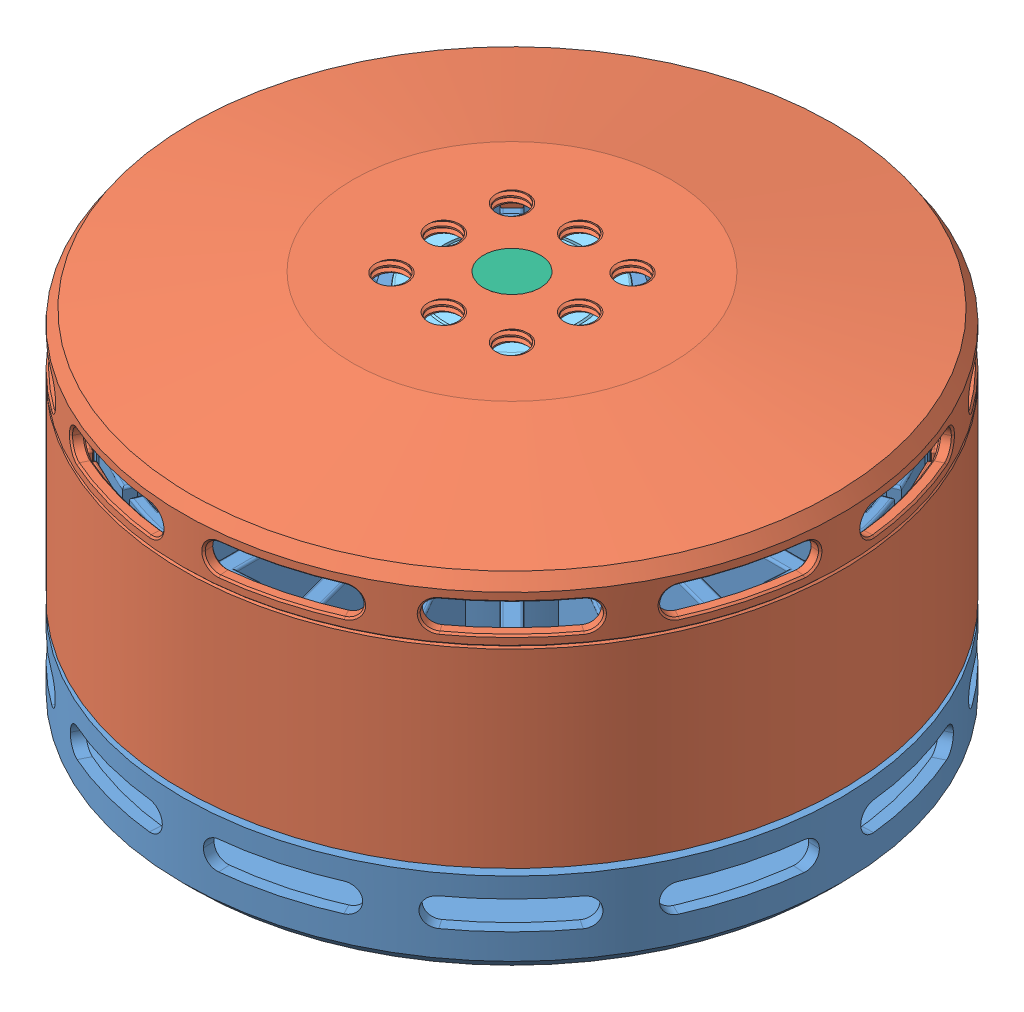
SolidWorks assembly MAD 5015 IPE V3 Motor Assembly, configuration Default. Lengths in mm.
Overall size (58 35.42 58).
29 component instances, 6 part files, 8 mates.
Components (placement in the parent):
- MAD 5015 IPE V3 Motor - Base-1: MAD 5015 IPE V3 Motor - Base [5015 IPE V3.0 ] at (22.8135 16.8969 43.0292) size (58 33.68 58)
- MAD 5015 IPE V3 Motor - Top-1: MAD 5015 IPE V3 Motor - Top [Default] at (22.8135 24.9802 43.0292) size (58 25.16 58)
- 696ZZ Bearing-1: 696ZZ Bearing [Default] at (22.7055 46.1225 47.1838) size (15.58 5 15.58)
  - ball bearing-3: ball bearing [Default] at (-8.9619 -2.7293 0.1818) x (0.444401 0.889708 -0.104533) z (0.713997 -0.281306 0.641152) size (2.7 2.7 2.7)
  - ball bearing-2: ball bearing [Default] at (-2.8221 2.4974 -4.5597) x (0.068858 0.146635 0.986791) z (-0.685148 -0.712022 0.153614) size (2.7 2.7 2.7)
  - ball bearing-1: ball bearing [Default] at (-3.7028 5.9901 -3.9309) x (0.28408 -0.958228 -0.033144) z (-0.506929 -0.179448 0.843102) size (2.7 2.7 2.7)
  - ball bearing-10: ball bearing [Default] at (-0.4124 2.7884 -8.0398) x (0.998941 0.024755 -0.038778) z (0.039629 -0.034863 0.998606) size (2.7 2.7 2.7)
  - ball bearing-8: ball bearing [Default] at (-3.307 1.4171 -7.6483) x (0.897908 0.343444 -0.27533) z (0.405535 -0.402192 0.820843) size (2.7 2.7 2.7)
  - ball bearing-7: ball bearing [Default] at (-7.5678 4.9126 -7.8607) x (0.925697 -0.372266 -0.067103) z (-0.05952 -0.318536 0.94604) size (2.7 2.7 2.7)
  - ball bearing-6: ball bearing [Default] at (0.3979 3.4094 -4.0154) x (0.993103 -0.041629 -0.109611) z (0.094371 -0.270991 0.957945) size (2.7 2.7 2.7)
  - ball bearing-9: ball bearing [Default] at (-6.0376 3.6584 -8.4022) x (0.983933 -0.065456 -0.166108) z (0.104106 -0.545494 0.831624) size (2.7 2.7 2.7)
  - ball bearing-4: ball bearing [Default] at (-2.7537 -0.7778 -2.9999) x (0.769778 0.563696 0.29948) z (-0.478994 0.20001 0.854728) size (2.7 2.7 2.7)
  - ball bearing-5: ball bearing [Default] at (-1.2092 -1.699 -1.9935) x (0.661202 0.749392 -0.034976) z (0.073954 -0.018714 0.997086) size (2.7 2.7 2.7)
  - 696ZZ Inner Bearing Race-1: 696ZZ Inner Bearing Race [Default] at (0.108 2.8577 -4.1547) size (9.15 5 9.15)
  - 696ZZ Outer Bearing Race-1: 696ZZ Outer Bearing Race [Default] at (0.108 2.8577 -4.1547) x (0.999209 0 0.039778) z (-0.039778 0 0.999209) size (15 5 15)
- 696ZZ Bearing-2: 696ZZ Bearing [Default] at (22.9417 20.6225 47.1833) x (0.998385 0 -0.056809) z (0.056809 0 0.998385) size (15.58 5 15.58)
  - ball bearing-3: ball bearing [Default] at (-8.9619 -2.7293 0.1818) x (0.444401 0.889708 -0.104533) z (0.713997 -0.281306 0.641152) size (2.7 2.7 2.7)
  - ball bearing-2: ball bearing [Default] at (-2.8221 2.4974 -4.5597) x (0.068858 0.146635 0.986791) z (-0.685148 -0.712022 0.153614) size (2.7 2.7 2.7)
  - ball bearing-1: ball bearing [Default] at (-3.7028 5.9901 -3.9309) x (0.28408 -0.958228 -0.033144) z (-0.506929 -0.179448 0.843102) size (2.7 2.7 2.7)
  - ball bearing-10: ball bearing [Default] at (-0.4124 2.7884 -8.0398) x (0.998941 0.024755 -0.038778) z (0.039629 -0.034863 0.998606) size (2.7 2.7 2.7)
  - ball bearing-8: ball bearing [Default] at (-3.307 1.4171 -7.6483) x (0.897908 0.343444 -0.27533) z (0.405535 -0.402192 0.820843) size (2.7 2.7 2.7)
  - ball bearing-7: ball bearing [Default] at (-7.5678 4.9126 -7.8607) x (0.925697 -0.372266 -0.067103) z (-0.05952 -0.318536 0.94604) size (2.7 2.7 2.7)
  - ball bearing-6: ball bearing [Default] at (0.3979 3.4094 -4.0154) x (0.993103 -0.041629 -0.109611) z (0.094371 -0.270991 0.957945) size (2.7 2.7 2.7)
  - ball bearing-9: ball bearing [Default] at (-6.0376 3.6584 -8.4022) x (0.983933 -0.065456 -0.166108) z (0.104106 -0.545494 0.831624) size (2.7 2.7 2.7)
  - ball bearing-4: ball bearing [Default] at (-2.7537 -0.7778 -2.9999) x (0.769778 0.563696 0.29948) z (-0.478994 0.20001 0.854728) size (2.7 2.7 2.7)
  - ball bearing-5: ball bearing [Default] at (-1.2092 -1.699 -1.9935) x (0.661202 0.749392 -0.034976) z (0.073954 -0.018714 0.997086) size (2.7 2.7 2.7)
  - 696ZZ Inner Bearing Race-1: 696ZZ Inner Bearing Race [Default] at (0.108 2.8577 -4.1547) size (9.15 5 9.15)
  - 696ZZ Outer Bearing Race-1: 696ZZ Outer Bearing Race [Default] at (0.108 2.8577 -4.1547) x (0.999209 0 0.039778) z (-0.039778 0 0.999209) size (15 5 15)
- Centre Shaft-2: Centre Shaft [Default] at (22.8135 18.4802 43.0292) x (0.999852 0 0.017194) z (-0.017194 0 0.999852) size (8 31.65 8)
Mates (geometry in assembly coordinates):
- Concentric1: concentric aligned: cylinder of 696ZZ Bearing-1/696ZZ Inner Bearing Race-1 through (22.8135 43.9767 43.0292) axis (0 1 0) radius 3; cylinder of Centre Shaft-2 through (22.8135 43.9802 43.0292) axis (0 1 0) radius 3
- Coincident1: coincident anti-aligned: plane of 696ZZ Bearing-1/696ZZ Inner Bearing Race-1 through (27.297 43.9802 43.0292) normal (0 -1 0); plane of Centre Shaft-2 through (22.8135 43.9802 43.0292) normal (0 1 0)
- Concentric2: concentric anti-aligned: cylinder of 696ZZ Bearing-2/696ZZ Inner Bearing Race-1 through (22.8135 18.4767 43.0292) axis (0 1 0) radius 3; cylinder of Centre Shaft-2 through (22.8135 23.4802 43.0292) axis (0 -1 0) radius 3
- Coincident3: coincident anti-aligned: plane of 696ZZ Bearing-2/696ZZ Inner Bearing Race-1 through (26.0083 23.4802 42.8474) normal (0 1 0); plane of Centre Shaft-2 through (22.8135 23.4802 43.0292) normal (0 -1 0)
- Concentric3: concentric anti-aligned: cylinder of MAD 5015 IPE V3 Motor - Base-1 through (22.8135 16.8969 43.0292) axis (0 -1 0) radius 7.5; cylinder of 696ZZ Bearing-2/696ZZ Outer Bearing Race-1 through (22.8135 18.479 43.0292) axis (0 1 0) radius 7.5
- Coincident4: coincident anti-aligned: plane of MAD 5015 IPE V3 Motor - Base-1 through (19.8135 23.4802 43.0292) normal (0 -1 0); plane of 696ZZ Bearing-2/696ZZ Outer Bearing Race-1 through (28.8561 23.4802 42.9261) normal (0 1 0)
- Concentric4: concentric anti-aligned: cylinder of MAD 5015 IPE V3 Motor - Top-1 through (22.8135 24.9802 43.0292) axis (0 -1 0) radius 2.5; cylinder of Centre Shaft-2 through (22.8135 48.9802 43.0292) axis (0 1 0) radius 2.5
- Coincident5: coincident anti-aligned: plane of MAD 5015 IPE V3 Motor - Top-1 through (20.3135 48.9802 43.0292) normal (0 -1 0); plane of Centre Shaft-2 through (22.8135 48.9802 43.0292) normal (0 1 0)
